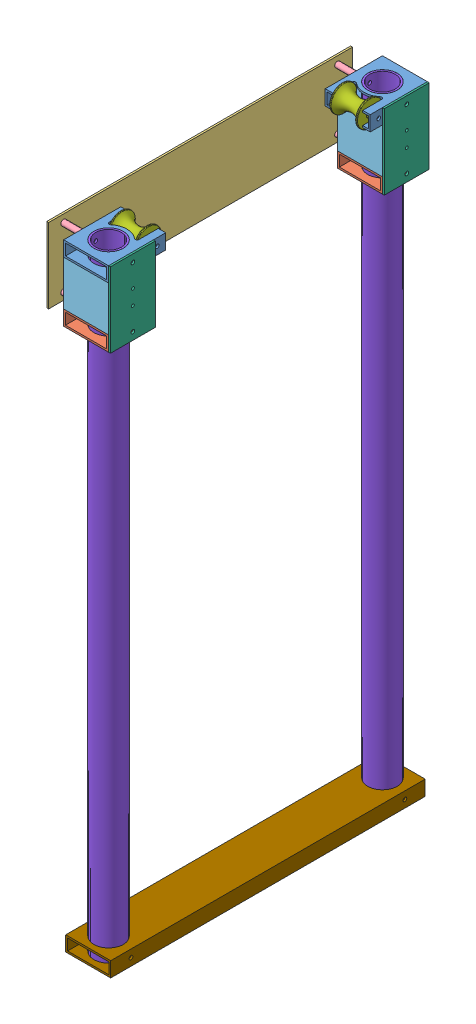
SolidWorks assembly 210-0000 Base Frame Asm, configuration Default. Lengths in mm.
Overall size (120.65 1057.02 540.61).
20 component instances, 10 part files, 8 mates.
Components (placement in the parent):
- 2110-000 Asm-1: 2110-000 Asm [Default] at (13.4445 1089.1023 -248.7499) x (1 0 0) z (0 -1 0) size (120.65 540.61 136.27)
  - 211-001-1: 211-001 [Default] at (9.4252 57.0126 71.5961) size (76.2 96.96 25.4)
  - 211-001-2: 211-001 [Default] at (85.6252 496.0186 71.5961) x (-1 0 0) z (0 0 1) size (76.2 96.96 25.4)
  - 211-002-1: 211-002 [Default] at (47.5252 44.3126 160.4961) x (1 0 0) z (0 -1 0) size (76.2 25.4 76.2)
  - 211-002-2: 211-002 [Default] at (47.5252 508.7186 160.4961) x (-1 0 0) z (0 1 0) size (76.2 25.4 76.2)
  - 211-003-1: 211-003 [Default] at (-28.6748 276.5156 109.6961) x (0 1 0) z (-1 0 0) size (515.21 127 3.17)
  - 211-004-1: 211-004 [Default] at (9.4252 44.3126 58.8961) x (0 0.953689 0.300795) z (-1 0 0) size (9.53 9.53 38.1)
  - 211-004-2: 211-004 [Default] at (9.4252 44.3126 160.4961) x (0 -0.738292 0.674482) z (-1 0 0) size (9.53 9.53 38.1)
  - 211-004-3: 211-004 [Default] at (-28.6748 508.7186 58.8961) x (0 0.989174 0.14675) z (1 0 0) size (9.53 9.53 38.1)
  - 211-004-4: 211-004 [Default] at (-28.6748 508.7186 160.4961) x (0 -0.917957 0.396679) z (1 0 0) size (9.53 9.53 38.1)
  - Part1^2110-000 Asm-1: Part1^2110-000 Asm [Rev 1.1] at origin (virtual)
  - 211-005-1: 211-005 [Default] at (47.5252 508.7186 109.6961) x (0 -1 0) z (0 0 -1) size (76.2 76.2 76.2)
  - 211-005-2: 211-005 [Default] at (47.5252 44.3126 109.6961) x (0 -1 0) z (0 0 -1) size (76.2 76.2 76.2)
  - 211-006-1: 211-006 [Default] at (88.8002 82.4126 46.1961) x (0 -1 0) z (0 0 1) size (76.2 3.17 127)
  - 211-006-2: 211-006 [Default] at (88.8002 546.8186 46.1961) x (0 -1 0) z (0 0 1) size (76.2 3.17 127)
  - 200-001 Roller 3-1: 200-001 Roller 3 [Default] at (47.5252 464.2686 58.8961) x (0 1 0) z (0 0 1) size (43.94 46.98 43.94)
  - 200-001 Roller 3-2: 200-001 Roller 3 [Default] at (47.5252 88.7626 58.8961) x (0 -1 0) z (0 0 1) size (43.94 46.98 43.94)
- 210-002 Rod-1: 210-002 Rod [Default] at (60.9698 -4.8437 259.9687) x (-1 0 0) z (0 0 -1) size (49.94 1047.75 49.94)
- 210-002 Rod-2: 210-002 Rod [Default] at (60.9698 -4.8437 -204.4372) x (-1 0 0) z (0 0 -1) size (49.94 1047.75 49.94)
- 200-001 Base Elevator-1: 200-001 Base Elevator [Default] at (60.9698 7.8563 -238.9343) size (76.2 25.4 533.4)
Mates (geometry in assembly coordinates):
- Concentric1: concentric: cylinder of 2110-000 Asm-1/211-001-2 through (60.9698 990.3283 259.9687) axis (0 1 0) radius 24.972; cylinder of 210-002 Rod-1 through (60.9698 1042.9063 259.9687) axis (0 -1 0) radius 21.797
- Concentric2: concentric: cylinder of 2110-000 Asm-1/211-001-1 through (60.9698 990.3283 -204.4372) axis (0 1 0) radius 24.972; cylinder of 210-002 Rod-2 through (60.9698 1042.9063 -204.4372) axis (0 -1 0) radius 21.797
- Concentric4: concentric: cylinder of 210-002 Rod-1 through (60.9698 1042.9063 259.9687) axis (0 -1 0) radius 21.797; cylinder of 200-001 Base Elevator-1 through (60.9698 -4.8437 259.9687) axis (0 1 0) radius 24.972
- Coincident5: coincident: plane of 210-002 Rod-2 through (60.9698 -4.8437 -204.4372) normal (0 -1 0); plane of 200-001 Base Elevator-1 through (22.8698 -4.8437 294.4657) normal (0 -1 0)
- Coincident6: coincident: plane of 210-002 Rod-1 through (60.9698 -4.8437 259.9687) normal (0 -1 0); plane of 200-001 Base Elevator-1 through (22.8698 -4.8437 294.4657) normal (0 -1 0)
- Coincident7: coincident: plane of 2110-000 Asm-1/211-001-2 through (99.0698 1042.9063 196.4687) normal (0 1 0); plane of 210-002 Rod-1 through (60.9698 1042.9063 259.9687) normal (0 1 0)
- Concentric6: concentric: cylinder of 210-002 Rod-2 through (85.9418 7.8563 -204.4372) axis (-1 0 0) radius 3.1115; cylinder of 200-001 Base Elevator-1 through (22.8698 7.8563 -204.4372) axis (1 0 0) radius 3.175
- Concentric7: concentric: cylinder of 210-002 Rod-1 through (85.9418 7.8563 259.9687) axis (-1 0 0) radius 3.1115; cylinder of 200-001 Base Elevator-1 through (22.8698 7.8563 259.9687) axis (1 0 0) radius 3.175
